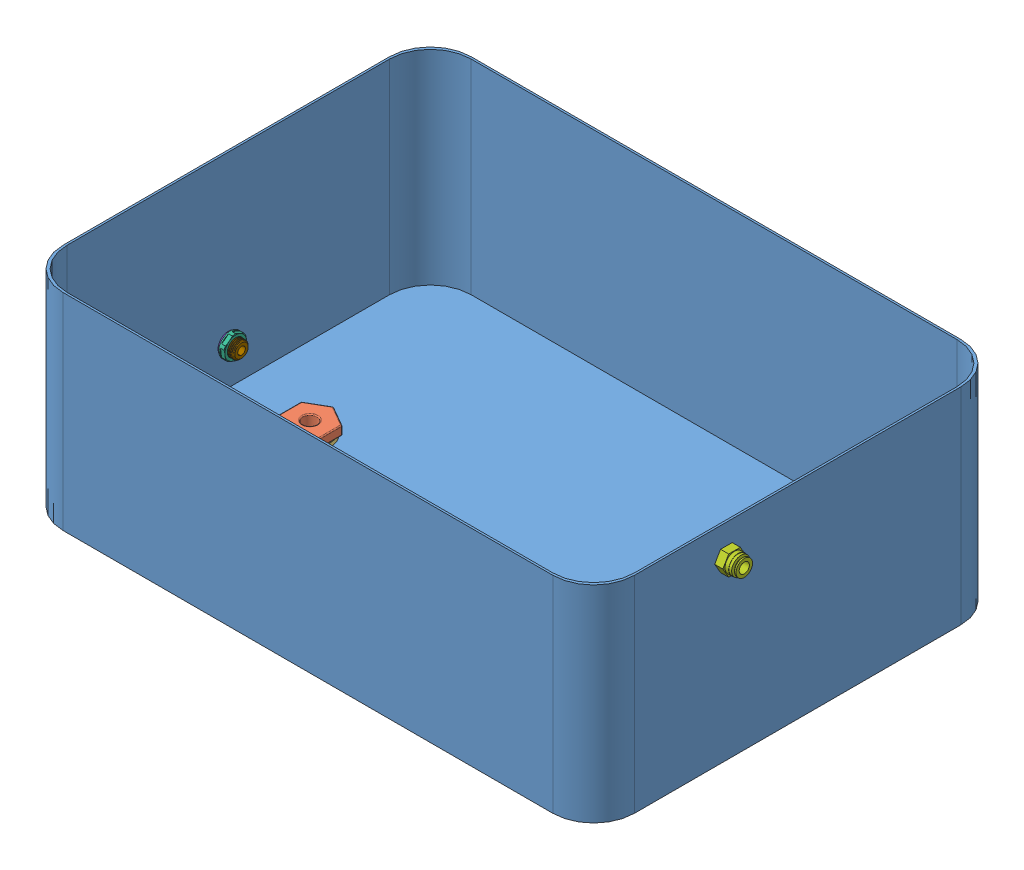
SolidWorks assembly reservroir_assembly, configuration Default. Lengths in mm.
Overall size (783.72 355.76 508).
15 component instances, 10 part files, 15 mates.
Components (placement in the parent):
- 20gal_reservoir-1: 20gal_reservoir [Default] at (-91.6687 -121.2967 45.3604) size (711.2 256.54 508)
- drain_assembly-1: drain_assembly [Default] at (-315.6747 -184.274 -9.0863) x (0.866025 0 0.5) z (-0.5 0 0.866025) size (58.27 70.14 50.8)
  - drain-1: drain [Default] at (3.4475 67.5493 60.8792) size (58.27 70.14 50.8)
  - drain_gasket-1: drain_gasket [Default] at (3.4475 62.9773 60.8792) size (50.8 4.57 50.8)
  - drain_nut-1: drain_nut [Default] at (3.4475 60.4373 60.8792) x (-1 0 0) z (0 0 1) size (58.11 25.4 50.8)
- TRUE_NIPPLE-1: TRUE_NIPPLE [4830K171] at (-343.1287 -176.2786 45.3604) x (0 1 0) z (0 0 1) size (28.84 22.41 22.44)
- straight_assembly-1: straight_assembly [Default] at (299.7617 137.5908 200.305) x (0 0.5 0.866025) z (-1 0 0) size (37.62 36.2 41.4)
  - true_npt_nut-1: true_npt_nut [3185K112] at (-78.6901 -4.206 40.9866) size (28.95 28.95 10.31)
  - through-wall-black-1: through-wall-black [Default] at (-78.6901 -4.206 35.8304) x (0.866025 0.5 0) z (-0.5 0.866025 0) size (28.96 41.4 25.08)
  - hrd-050-gasket-1: hrd-050-gasket [Default] at (-78.6901 -4.206 40.9866) x (0.974895 0.222665 0) z (-0.222665 0.974895 0) size (25.4 2.62 25.4)
- 90_assembly-1: 90_assembly [Default] at (-431.71 -60.3147 50.82) x (0 -0.123783 0.992309) z (1 0 0) size (52.61 48.36 69.22)
  - true_npt_nut-1: true_npt_nut [3185K112] at (-3.8428 13.2999 -10.4025) size (28.95 28.95 10.31)
  - hrd-050-gasket-1: hrd-050-gasket [Default] at (-3.8428 13.2999 -13.0187) x (0.930255 -0.366913 0) z (-0.366913 -0.930255 0) size (25.4 2.62 25.4)
  - through-wall-90-1: through-wall-90 [Default] at (-3.8428 13.2999 -15.5587) x (-0.797473 0.603354 0) z (-0.603354 -0.797473 0) size (46.99 69.22 25.08)
- threaded_threaded_90-1: threaded_threaded_90 [Default] at (-311.3787 -209.1625 45.3604) x (0 -1 0) z (1 0 0) size (46.22 27.78 46.59)
Mates (geometry in assembly coordinates):
- Concentric1: concentric anti-aligned: circle of 20gal_reservoir-1; circle of drain_assembly-1/drain-1
- Parallel1: parallel aligned: plane of 20gal_reservoir-1 through (-444.7287 132.7033 296.8204) normal (1 0 0); plane of drain_assembly-1/drain-1 through (-317.7287 -105.2947 60.0251) normal (1 0 0)
- Coincident2: coincident anti-aligned: plane of 20gal_reservoir-1 through (-91.6687 -123.8367 45.3604) normal (0 -1 0); plane of drain_assembly-1/drain_nut-1 through (-343.1287 -123.8367 45.3604) normal (0 1 0)
- Concentric2: concentric anti-aligned: circle of drain_assembly-1/drain-1; cylinder of TRUE_NIPPLE-1 through (-343.1287 -190.6979 45.3604) axis (0 1 0) radius 7.8994
- Coincident3: coincident anti-aligned: plane of drain_assembly-1/drain-1 through (-343.1287 -175.1447 45.3604) normal (0 -1 0); circle of TRUE_NIPPLE-1
- Coincident4: coincident anti-aligned: plane of 20gal_reservoir-1 through (263.9313 132.7033 299.3604) normal (1 0 0); plane of straight_assembly-1/through-wall-black-1 through (263.9313 94.6033 134.2604) normal (-1 0 0)
- Concentric3: concentric aligned: circle of 20gal_reservoir-1; cylinder of straight_assembly-1/through-wall-black-1 through (274.0913 94.6033 134.2604) axis (-1 0 0) radius 6.35
- Parallel2: parallel aligned: plane of 20gal_reservoir-1 through (-91.6687 132.7033 45.3604) normal (0 1 0); plane of straight_assembly-1/through-wall-black-1 through (274.0913 107.1446 127.0197) normal (0 1 0)
- Coincident6: coincident anti-aligned: plane of 20gal_reservoir-1 through (-444.7287 132.7033 296.8204) normal (1 0 0); plane of 90_assembly-1/hrd-050-gasket-1 through (-444.7287 -73.0367 45.3604) normal (-1 0 0)
- Concentric4: concentric anti-aligned: circle of 20gal_reservoir-1; circle of 90_assembly-1/hrd-050-gasket-1
- Parallel3: parallel aligned: plane of 20gal_reservoir-1 through (-447.2687 132.7033 -208.6396) normal (0 0 -1); plane of 90_assembly-1/through-wall-90-1 through (-457.4287 -65.796 32.8191) normal (0 0 -1)
- Parallel4: parallel anti-aligned: plane of drain_assembly-1/drain-1 through (-343.1287 -175.1447 45.3604) normal (0 -1 0); plane of threaded_threaded_90-1 through (-343.1287 -177.4125 45.3604) normal (0 1 0)
- Concentric5: concentric aligned: circle of drain_assembly-1/drain-1; circle of threaded_threaded_90-1
- Coincident8: coincident anti-aligned: plane of TRUE_NIPPLE-1 through (-343.1287 -177.4125 45.3604) normal (0 -1 0); plane of threaded_threaded_90-1 through (-343.1287 -177.4125 45.3604) normal (0 1 0)
- Parallel5: parallel aligned: plane of 20gal_reservoir-1 through (263.9313 132.7033 299.3604) normal (1 0 0); plane of threaded_threaded_90-1 through (-311.3787 -209.1625 45.3604) normal (1 0 0)
